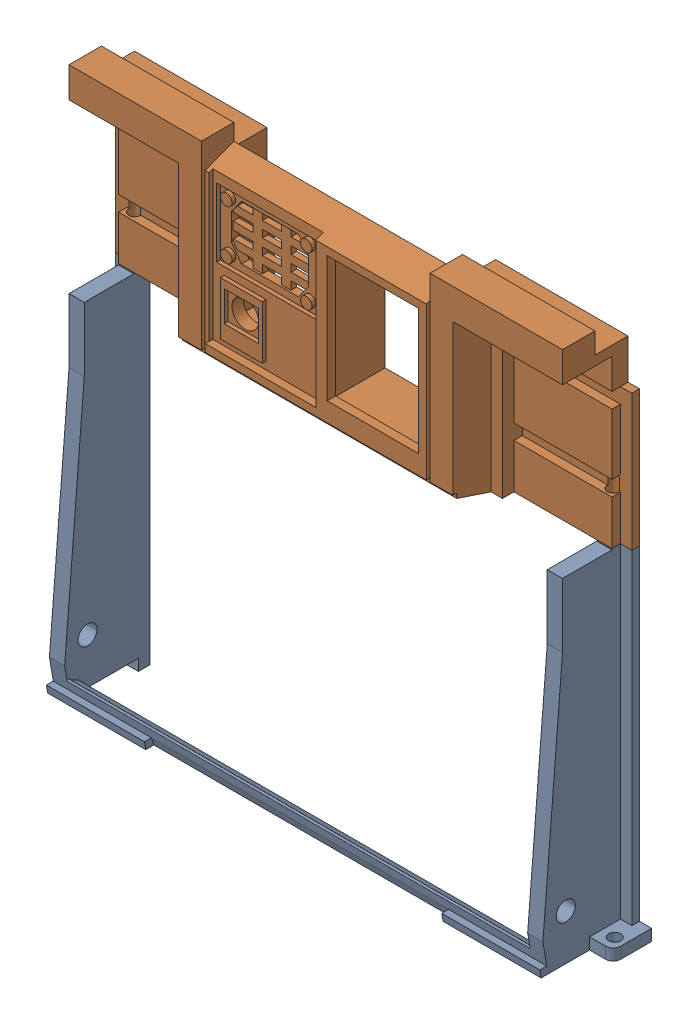
SolidWorks assembly body-front-split, configuration Default. Lengths in mm.
Overall size (236.5 238.33 38.58).
2 component instances, 2 part files, 1 mates.
Components (placement in the parent):
- body-front-bottom-1: body-front-bottom [Default] at (-101.0548 -3.9965 56.0404) size (236.5 152.17 38.58)
- body-front-top-1: body-front-top [Default] at (-101.0548 -3.9965 56.0404) size (225.83 95 28.67)
Mates (geometry in assembly coordinates):
- Coincident1: coincident anti-aligned: circle of body-front-bottom-1; circle of body-front-top-1
